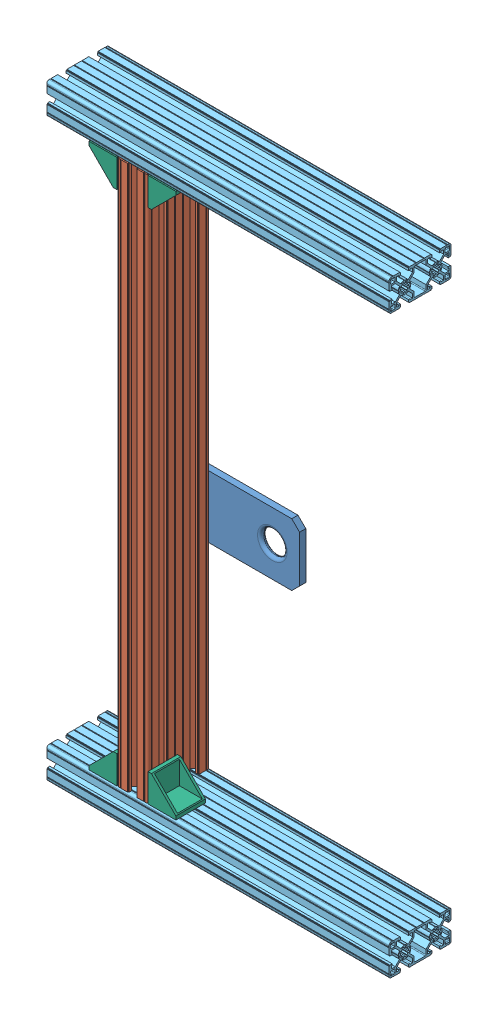
SolidWorks assembly assemblage profilé bague final, configuration Défaut. Lengths in mm.
Overall size (440 780 96).
12 component instances, 6 part files, 31 mates.
Components (placement in the parent):
- pièce support bague-1: pièce support bague [Défaut] at (-99.6725 54.2441 0) size (155 80 8)
- 700-1: 700 [Défaut] at (-79.6725 -175.7559 48) x (1 0 0) z (0 -1 0) size (40 80 700)
- vis fixation profile profile-1: vis fixation profile profile [Défaut] at (-79.6725 34.2441 0) x (-0.806158 0.591701 0) z (0 0 -1) size (13 13 26)
- vis fixation profile profile-2: vis fixation profile profile [Défaut] at (-79.6725 -5.7559 0) x (-0.923728 -0.383049 0) z (0 0 -1) size (13 13 26)
- écrous profilée m8-1: écrous profilée m8 [Défaut] at (-79.6725 -5.7559 12) x (-1 0 0) z (0 0 -1) size (13.8 23 7.3)
- écrous profilée m8-2: écrous profilée m8 [Défaut] at (-79.6725 34.2441 12) x (-1 0 0) z (0 0 -1) size (13.8 23 7.3)
- 440-1: 440 [Défaut] at (150.3275 -295.7559 48) x (0 1 0) z (1 0 0) size (40 80 440)
- 440-2: 440 [Défaut] at (-89.6725 444.2441 48) x (0 -1 0) z (-1 0 0) size (40 80 440)
- equerre 40x40-1: equerre 40x40 [Défaut] at (-59.6725 -275.7559 69) x (0 0 -1) z (0 1 0) size (38 36 36)
- equerre 40x40-2: equerre 40x40 [Défaut] at (-99.6725 -275.7559 69) x (0 0 1) z (0 1 0) size (38 36 36)
- equerre 40x40-3: equerre 40x40 [Défaut] at (-59.6725 424.2441 69) x (0 0 1) z (0 -1 0) size (38 36 36)
- equerre 40x40-4: equerre 40x40 [Défaut] at (-99.6725 424.2441 69) x (0 0 1) z (-1 0 0) size (38 36 36)
Mates (geometry in assembly coordinates):
- Coïncidente1: coincident anti-aligned: plane of pièce support bague-1 through (-99.6725 -25.7559 8) normal (0 0 1); plane of 700-1 through (-73.6725 424.2441 8) normal (0 0 -1)
- Distance1: distance = 250 mm aligned: plane of 700-1 through (-79.6725 -275.7559 68) normal (0 -1 0); plane of pièce support bague-1 through (-99.6725 -25.7559 8) normal (0 -1 0)
- Coïncidente3: coincident aligned: plane of pièce support bague-1 through (-99.6725 54.2441 8) normal (-1 0 0); plane of 700-1 through (-99.6725 424.2441 22) normal (-1 0 0)
- Coaxiale1: concentric anti-aligned: cylinder of pièce support bague-1 through (-79.6725 -5.7559 8) axis (0 0 1) radius 4.5; cylinder of vis fixation profile profile-2 through (-79.6725 -5.7559 18) axis (0 0 -1) radius 4
- Coïncidente4: coincident anti-aligned: plane of pièce support bague-1 through (-99.6725 -25.7559 0) normal (0 0 -1); plane of vis fixation profile profile-2 through (-82.1623 0.2484 0) normal (0 0 1)
- Coaxiale2: concentric anti-aligned: cylinder of pièce support bague-1 through (-79.6725 34.2441 8) axis (0 0 1) radius 4.5; cylinder of vis fixation profile profile-1 through (-79.6725 34.2441 18) axis (0 0 -1) radius 4
- Coïncidente5: coincident anti-aligned: plane of pièce support bague-1 through (-99.6725 -25.7559 0) normal (0 0 -1); plane of vis fixation profile profile-1 through (-75.8264 39.4842 0) normal (0 0 1)
- Coaxiale4: concentric aligned: cylinder of vis fixation profile profile-2 through (-79.6725 -5.7559 18) axis (0 0 -1) radius 4; cylinder of écrous profilée m8-1 through (-79.6725 -5.7559 15.7) axis (0 0 -1) radius 4
- Parallèle4: parallel aligned: plane of 700-1 through (-79.6725 -275.7559 68) normal (0 -1 0); plane of écrous profilée m8-1 through (-79.6725 -13.2559 14.6013) normal (0 -1 0)
- Coïncidente9: coincident anti-aligned: plane of 700-1 through (-72.6725 424.2441 12) normal (0 0 1); plane of écrous profilée m8-1 through (-72.7725 9.7441 12) normal (0 0 -1)
- Coaxiale5: concentric aligned: cylinder of vis fixation profile profile-1 through (-79.6725 34.2441 18) axis (0 0 -1) radius 4; cylinder of écrous profilée m8-2 through (-79.6725 34.2441 15.7) axis (0 0 -1) radius 4
- Parallèle5: parallel aligned: plane of 700-1 through (-79.6725 424.2441 68) normal (0 1 0); plane of écrous profilée m8-2 through (-79.6725 49.7441 14.6013) normal (0 1 0)
- Coïncidente11: coincident anti-aligned: plane of 700-1 through (-84.6725 424.2441 12) normal (0 0 1); plane of écrous profilée m8-2 through (-72.7725 49.7441 12) normal (0 0 -1)
- Coïncidente12: coincident anti-aligned: plane of 700-1 through (-79.6725 -275.7559 68) normal (0 -1 0); plane of 440-1 through (-189.6725 -275.7559 43.5) normal (0 1 0)
- Coïncidente13: coincident aligned: plane of 700-1 through (-65.1725 424.2441 88) normal (0 0 1); plane of 440-1 through (-189.6725 -301.7559 88) normal (0 0 1)
- Coïncidente14: coincident anti-aligned: plane of 700-1 through (-79.6725 424.2441 68) normal (0 1 0); plane of 440-2 through (250.3275 424.2441 43.5) normal (0 -1 0)
- Coïncidente15: coincident aligned: plane of 700-1 through (-65.1725 424.2441 88) normal (0 0 1); plane of 440-2 through (250.3275 450.2441 88) normal (0 0 1)
- Distance2: distance = 130 mm anti-aligned: plane of 440-1 through (-189.6725 -295.7559 68) normal (-1 0 0); plane of 700-1 through (-59.6725 424.2441 53.5) normal (1 0 0)
- Distance3: distance = 130 mm anti-aligned: plane of 700-1 through (-59.6725 424.2441 43.5) normal (1 0 0); plane of 440-2 through (-189.6725 444.2441 68) normal (-1 0 0)
- Coïncidente18: coincident anti-aligned: plane of 700-1 through (-59.6725 424.2441 74) normal (1 0 0); plane of equerre 40x40-1 through (-59.6725 -275.7559 88) normal (-1 0 0)
- Coïncidente19: coincident anti-aligned: plane of 440-1 through (-189.6725 -275.7559 74) normal (0 1 0); plane of equerre 40x40-1 through (-23.6725 -275.7559 88) normal (0 -1 0)
- Coïncidente20: coincident aligned: plane of 700-1 through (-65.1725 424.2441 88) normal (0 0 1); plane of equerre 40x40-1 through (-23.6725 -275.7559 88) normal (0 0 1)
- Coïncidente21: coincident anti-aligned: plane of 700-1 through (-99.6725 424.2441 82.5) normal (-1 0 0); plane of equerre 40x40-2 through (-99.6725 -275.7559 50) normal (1 0 0)
- Coïncidente22: coincident anti-aligned: plane of 440-1 through (-189.6725 -275.7559 74) normal (0 1 0); plane of equerre 40x40-2 through (-135.6725 -275.7559 50) normal (0 -1 0)
- Coïncidente23: coincident aligned: plane of 700-1 through (-85.6725 424.2441 88) normal (0 0 1); plane of equerre 40x40-2 through (-135.6725 -275.7559 88) normal (0 0 1)
- Coïncidente24: coincident anti-aligned: plane of 700-1 through (-59.6725 424.2441 74) normal (1 0 0); plane of equerre 40x40-3 through (-59.6725 424.2441 50) normal (-1 0 0)
- Coïncidente25: coincident anti-aligned: plane of 440-2 through (250.3275 424.2441 74) normal (0 -1 0); plane of equerre 40x40-3 through (-23.6725 424.2441 50) normal (0 1 0)
- Coïncidente26: coincident aligned: plane of 700-1 through (-65.1725 424.2441 88) normal (0 0 1); plane of equerre 40x40-3 through (-23.6725 424.2441 88) normal (0 0 1)
- Coïncidente27: coincident anti-aligned: plane of 440-2 through (250.3275 424.2441 74) normal (0 -1 0); plane of equerre 40x40-4 through (-99.6725 424.2441 50) normal (0 1 0)
- Coïncidente28: coincident anti-aligned: plane of 700-1 through (-99.6725 424.2441 82.5) normal (-1 0 0); plane of equerre 40x40-4 through (-99.6725 388.2441 50) normal (1 0 0)
- Coïncidente29: coincident aligned: plane of 700-1 through (-85.6725 424.2441 88) normal (0 0 1); plane of equerre 40x40-4 through (-99.6725 388.2441 88) normal (0 0 1)
